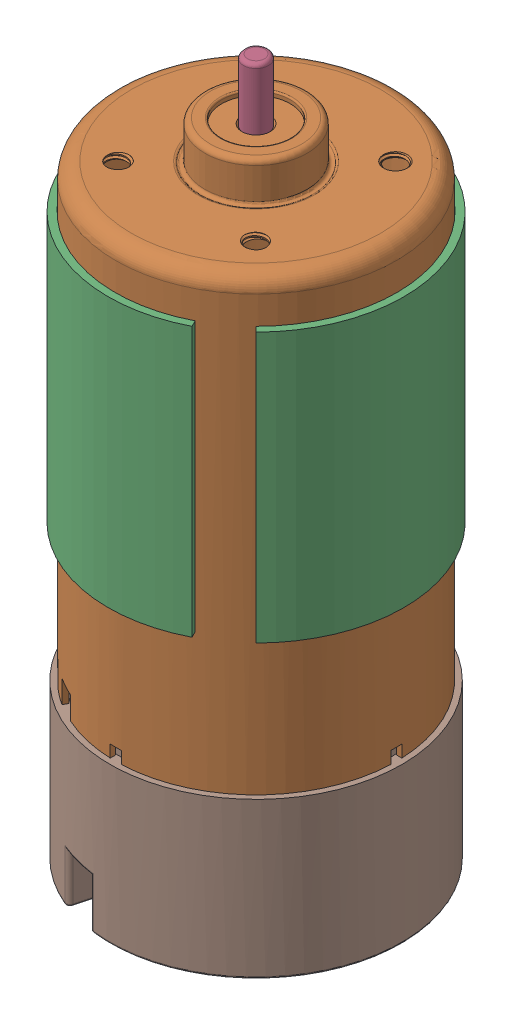
SolidWorks assembly 5000-0002-0001, configuration Default. Lengths in mm.
Overall size (52.36 95.65 52.36).
18 component instances, 10 part files, 0 mates.
Components (placement in the parent):
- 5000-0002-0001 encoder cap-1: 5000-0002-0001 encoder cap [Default] x (0 1 0) z (0 0 1) size (29.66 52.33 52.33)
  - JST-XH-4POS-VERT (1)-1: JST-XH-4POS-VERT (1) [Default] at (2.8 12.25 -75.95) x (1 0 0) z (0 0 -1) size (10.4 12.83 12.83)
    - Plastic (1)-1: Plastic (1) [Default] at (-6.1146 -33.6358 -52.1967) x (0 0.707107 0.707107) z (-1 0 0) size (12.4 5.75 7)
    - Pin (1)-1: Pin (1) [Default] at (-7.7146 -29.3225 -51.2067) x (0 0.707107 0.707107) z (-1 0 0) size (0.64 0.64 10)
    - Pin (1)-2: Pin (1) [Default] at (-7.7146 -34.6258 -56.51) x (0 0.707107 0.707107) z (-1 0 0) size (0.64 0.64 10)
    - Pin (1)-3: Pin (1) [Default] at (-7.7146 -32.858 -54.7423) x (0 0.707107 0.707107) z (-1 0 0) size (0.64 0.64 10)
    - Pin (1)-4: Pin (1) [Default] at (-7.7146 -31.0902 -52.9745) x (0 0.707107 0.707107) z (-1 0 0) size (0.64 0.64 10)
  - screw-1: screw [Default] at (-41.264 -8.1646 3.9905) x (0.882398 0 0.470504) z (0 -1 0) size (8.9 7.87 4.95)
    - 99461A915_Phillips Rounded Head Thread-Forming Screws (1)-1: 99461A915_Phillips Rounded Head Thread-Forming Screws (1) [Default] at (27.264 -14.6475 -49.347) x (-0.332697 -0.623949 0.707107) z (-0.882398 0.470504 0) size (3.5 3.5 7.44)
  - screw_1-1: screw_1 [Default] at (-14.4172 7.3354 3.9905) x (0.882398 0 0.470504) z (0 -1 0) size (8.9 7.87 4.95)
    - 99461A915_Phillips Rounded Head Thread-Forming Screws (1)-1: 99461A915_Phillips Rounded Head Thread-Forming Screws (1) [Default] at (-10.5142 -28.4382 -25.8237) x (-0.332697 -0.623949 0.707107) z (-0.882398 0.470504 0) size (3.5 3.5 7.44)
  - endcap-1: endcap [Default] at (72.6354 37.1707 -11.0784) x (0 -0.707107 -0.707107) z (1 0 0) size (37 37 21.84)
  - base-1: base [Default] at (-55.8646 37.1707 -11.0784) x (0 -0.707107 -0.707107) z (-1 0 0) size (34.96 34.31 1)
  - M+-1: M+ [Default] at origin size (20.32 2.82 2.82)
  - M--1: M- [Default] at (2.2506 -4.5179 -19.3049) size (20.32 2.82 2.82)
- 5000-0002-0001 body-1: 5000-0002-0001 body [Default] at (-37.1707 3.4854 -11.0784) size (35.61 61.8 35.61)
- 5000-0002-0001 motor shield-1: 5000-0002-0001 motor shield [Default] at (-37.1707 54.6354 -11.0784) x (0.808104 0 -0.58904) z (0 -1 0) size (37.5 37.27 34.15)
- 5000-0002-0001 motor shaft-1: 5000-0002-0001 motor shaft [Default] at (-37.1707 59.4854 -11.0784) size (3.14 12.53 3.14)
